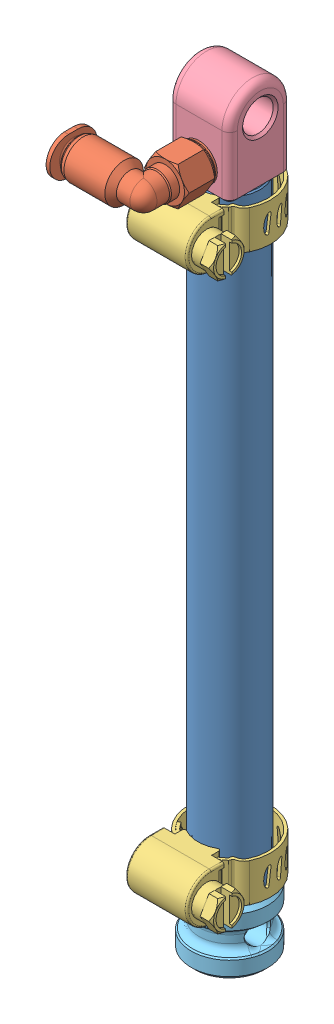
SolidWorks assembly AARL_QR_PN_PA_BR_AN_EX-Extensor, configuration Default. Lengths in mm.
Overall size (26.6 158.75 31.28).
6 component instances, 5 part files, 15 mates.
Components (placement in the parent):
- AARL_QR_PN_PA_BR_AN_EX_001-1: AARL_QR_PN_PA_BR_AN_EX_001 [Resting] at origin size (12.7 127 12.7)
- AARL_Puppy_18_02_57_010-QSML-M3-4-1: AARL_Puppy_18_02_57_010-QSML-M3-4 [Default] at (0 68.2625 17.85) x (-1 0 0) z (0 0 -1) size (20.32 8 18.9)
- AARL_Puppy_18_02_57_011-5388K140_Hose-Clamp-1: AARL_Puppy_18_02_57_011-5388K140_Hose-Clamp [5388K14] at (0 -58.547 0) x (1 0 0) z (0 -1 0) size (19.43 23.71 9.91)
- AARL_Puppy_18_02_57_011-5388K140_Hose-Clamp-2: AARL_Puppy_18_02_57_011-5388K140_Hose-Clamp [5388K14] at (0 58.547 0) x (1 0 0) z (0 -1 0) size (19.43 23.71 9.91)
- AARL_QR_PN_EP_001-1: AARL_QR_PN_EP_001 [Default] at (0 76.2 0) x (0 0 1) z (-1 0 0) size (12.7 31.75 12.7)
- AARL_QR_PN_EP_002-1: AARL_QR_PN_EP_002 [Default] at (0 -63.5 0) x (-1 0 0) z (0 0 1) size (15.88 25.4 15.88)
Mates (geometry in assembly coordinates):
- Concentric1: concentric aligned: cylinder of AARL_QR_PN_PA_BR_AN_EX_001-1 through (0 11.6086 0) axis (0 1 0) radius 4.7625; cylinder of AARL_QR_PN_EP_001-1 through (0 85.744 0) axis (0 1 0) radius 4.3656
- Coincident1: coincident anti-aligned: plane of AARL_QR_PN_PA_BR_AN_EX_001-1 through (4.7625 63.5 0) normal (0 1 0); plane of AARL_QR_PN_EP_001-1 through (-6.35 63.5 -6.35) normal (0 -1 0)
- Parallel1: parallel aligned: plane of AARL_QR_PN_EP_001-1 through (-6.35 63.5 6.35) normal (0 0 1)
- Concentric2: concentric aligned: cylinder of AARL_Puppy_18_02_57_010-QSML-M3-4-1 through (0 68.2625 6.35) axis (0 0 1) radius 1.5; cylinder of AARL_QR_PN_EP_001-1 through (0 68.2625 6.35) axis (0 0 1) radius 2.0193
- Coincident3: coincident anti-aligned: plane of AARL_Puppy_18_02_57_010-QSML-M3-4-1 through (0 68.2625 6.35) normal (0 0 -1); plane of AARL_QR_PN_EP_001-1 through (-6.35 63.5 6.35) normal (0 0 1)
- Parallel2: parallel aligned: plane of AARL_Puppy_18_02_57_010-QSML-M3-4-1 through (2.3094 64.2625 13.4056) normal (0 -1 0); plane of AARL_QR_PN_EP_001-1 through (-6.35 63.5 -6.35) normal (0 -1 0)
- Concentric3: concentric aligned: cylinder of AARL_QR_PN_PA_BR_AN_EX_001-1 through (0 11.6086 0) axis (0 1 0) radius 6.35; cylinder of AARL_Puppy_18_02_57_011-5388K140_Hose-Clamp-2 through (0 54.5783 0) axis (0 1 0) radius 7.9375
- Coincident5: coincident aligned: plane of AARL_Puppy_18_02_57_011-5388K140_Hose-Clamp-2 through (6.35 58.547 10.2337) normal (1 0 0); plane of AARL_QR_PN_EP_001-1 through (6.35 76.2 0) normal (1 0 0)
- Coincident6: coincident anti-aligned: plane of AARL_Puppy_18_02_57_011-5388K140_Hose-Clamp-2 through (0 63.5 0) normal (0 1 0); plane of AARL_QR_PN_EP_001-1 through (-6.35 63.5 -6.35) normal (0 -1 0)
- Concentric4: concentric anti-aligned: cylinder of AARL_QR_PN_PA_BR_AN_EX_001-1 through (0 11.6086 0) axis (0 1 0) radius 4.7625; cylinder of AARL_QR_PN_EP_002-1 through (0 -71.2377 0) axis (0 -1 0) radius 4.3656
- Coincident7: coincident anti-aligned: plane of AARL_QR_PN_PA_BR_AN_EX_001-1 through (6.35 -63.5 0) normal (0 -1 0); plane of AARL_QR_PN_EP_002-1 through (-4.3656 -63.5 0) normal (0 1 0)
- Parallel3: parallel anti-aligned: cylinder of AARL_QR_PN_EP_001-1 through (-6.35 76.2 0) axis (1 0 0) radius 3.175; cylinder of AARL_QR_PN_EP_002-1 through (7.9375 -69.85 0) axis (-1 0 0) radius 2.3813
- Concentric6: concentric aligned: cylinder of AARL_QR_PN_PA_BR_AN_EX_001-1 through (0 11.6086 0) axis (0 1 0) radius 6.35; cylinder of AARL_Puppy_18_02_57_011-5388K140_Hose-Clamp-1 through (0 -62.5157 0) axis (0 1 0) radius 7.9375
- Coincident8: coincident aligned: plane of AARL_Puppy_18_02_57_011-5388K140_Hose-Clamp-1 through (6.35 -58.547 10.2337) normal (1 0 0); plane of AARL_Puppy_18_02_57_011-5388K140_Hose-Clamp-2 through (6.35 58.547 10.2337) normal (1 0 0)
- Coincident9: coincident anti-aligned: plane of AARL_Puppy_18_02_57_011-5388K140_Hose-Clamp-1 through (0 -63.5 0) normal (0 -1 0); plane of AARL_QR_PN_EP_002-1 through (-4.3656 -63.5 0) normal (0 1 0)
